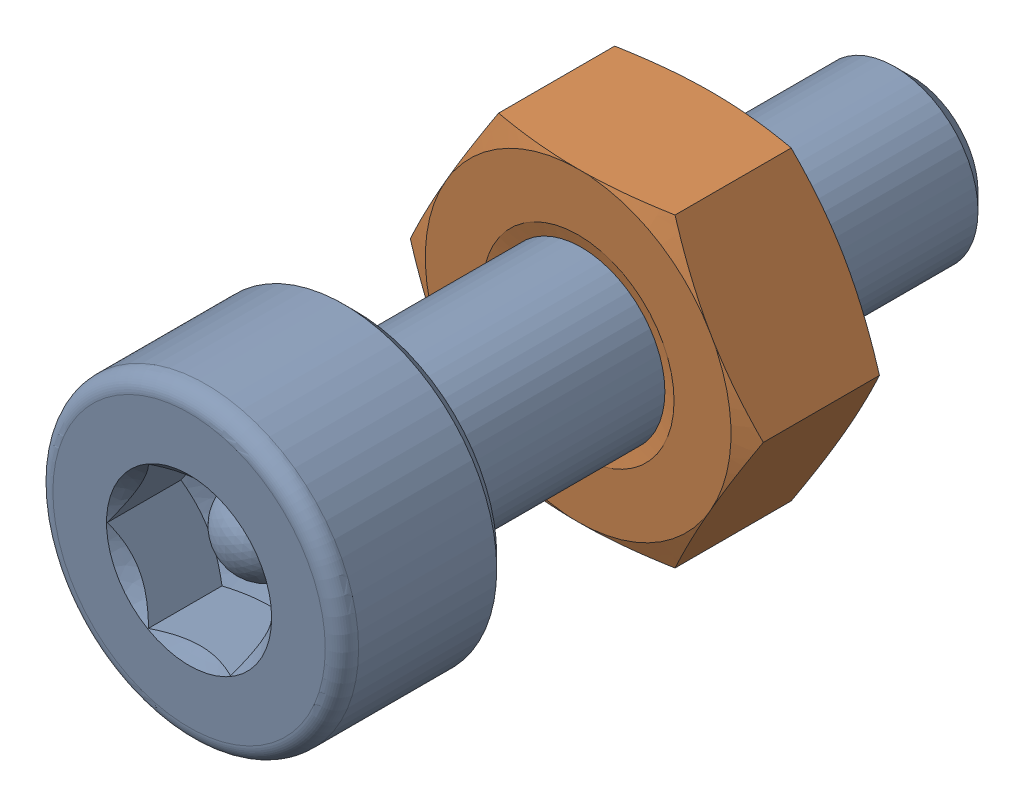
SolidWorks assembly Screw and Nut M3x010_020, configuration Varsayılan. Lengths in mm.
Overall size (6.35 5.5 13.14).
2 component instances, 2 part files, 0 mates.
Components (placement in the parent):
- M3x10-Screw019-1: M3x10-Screw019 [Varsayılan] at origin size (5.5 5.5 13.14)
- M3-Nut051-1: M3-Nut051 [Varsayılan] at (0 0 -4) x (-1 0 0) z (0 0 -1) size (6.35 5.5 2.4)
